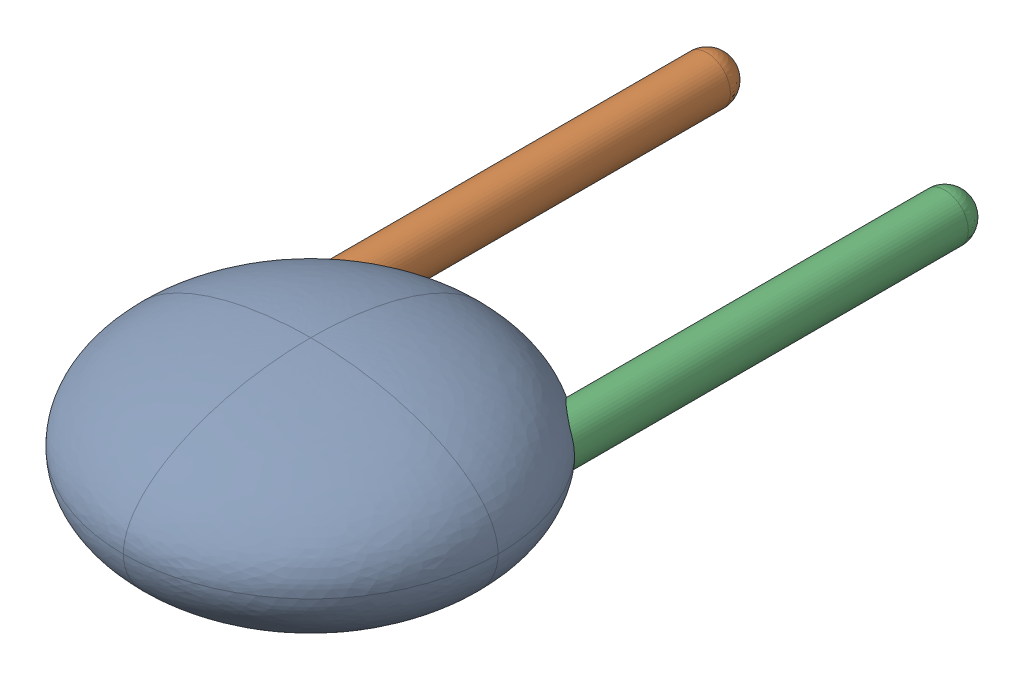
SolidWorks assembly C1, configuration Défaut. Lengths in mm.
Overall size (4 2 7.75).
4 component instances, 3 part files, 0 mates.
Components (placement in the parent):
- Open CASCADE STEP translator 6.8 1.3.1-1: Open CASCADE STEP translator 6.8 1.3.1 [Défaut] at origin size (4 2 7.75)
  - Body_1_2-1: Body_1_2 [Défaut] at (1.27 -1.27 0) x (0 1 0) z (0 0 1) size (2 4 4)
  - Pin_1-1: Pin_1 [Défaut] x (0 -1 0) z (0 0 1) size (0.5 0.5 5.5)
  - Pin_2-1: Pin_2 [Défaut] at (2.54 2.54 0) x (0 -1 0) z (0 0 1) size (0.5 0.5 5.5)
